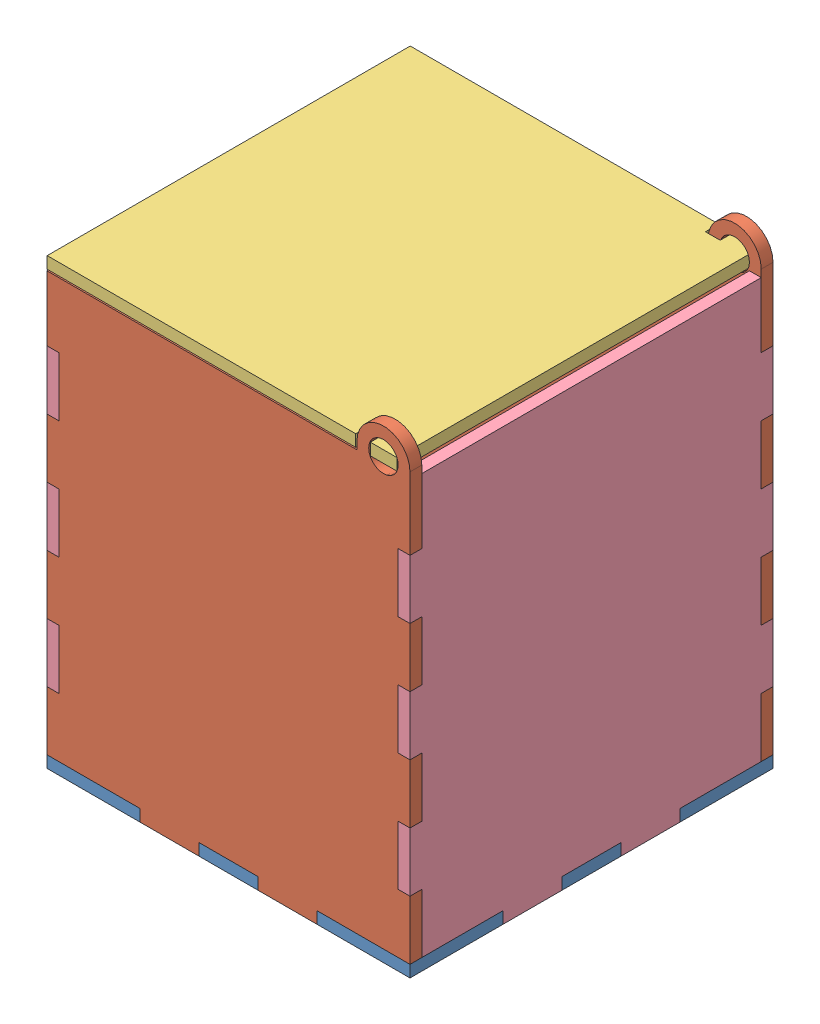
SolidWorks assembly Сборка122, configuration По умолчанию. Lengths in mm.
Overall size (123 157.5 123).
6 component instances, 4 part files, 16 mates.
Components (placement in the parent):
- Дно-1: Дно [По умолчанию] at origin size (123 4 123)
- БокСОтв-1: БокСОтв [По умолчанию] at (0 4 -4) size (123 157.5 4)
- БокСОтв-2: БокСОтв [По умолчанию] at (0 4 -123) size (123 157.5 4)
- Крышка-1: Крышка [По умолчанию] at (0.0826 150.5 -61.5) x (0 0 -1) z (-1 0 0) size (123 4 118.5)
- ПередСтенка-1: ПередСтенка [По умолчанию] at (0 4 -4) x (0 0 -1) z (1 0 0) size (123 146 4)
- ПередСтенка-2: ПередСтенка [По умолчанию] at (119 4 -4) x (0 0 -1) z (1 0 0) size (123 146 4)
Mates (geometry in assembly coordinates):
- Совпадение1: coincident aligned: plane of Дно-1 through (0 4 0) normal (0 0 1); plane of БокСОтв-1 through (114 148.5 0) normal (0 0 1)
- Совпадение2: coincident aligned: plane of Дно-1 through (0 0 0) normal (0 -1 0); plane of БокСОтв-1 through (71.5 0 0) normal (0 -1 0)
- Совпадение3: coincident aligned: plane of Дно-1 through (123 4 0) normal (1 0 0); plane of БокСОтв-1 through (123 4 0) normal (1 0 0)
- Совпадение4: coincident aligned: plane of БокСОтв-1 through (0 4 0) normal (-1 0 0); plane of БокСОтв-2 through (0 4 -119) normal (-1 0 0)
- Совпадение5: coincident aligned: plane of Дно-1 through (51.5 4 -123) normal (0 0 -1); plane of БокСОтв-2 through (114 148.5 -123) normal (0 0 -1)
- Совпадение6: coincident aligned: plane of Дно-1 through (0 0 0) normal (0 -1 0); plane of БокСОтв-2 through (31.5 0 -119) normal (0 -1 0)
- Совпадение7: coincident: cylinder of БокСОтв-1 through (114 148.5 0) axis (0 0 -1) radius 5; line of Крышка-1 through (118.5826 146.5 -123) axis (0 0 1)
- Совпадение8: coincident aligned: plane of БокСОтв-1 through (114 148.5 0) normal (0 0 1); plane of Крышка-1 through (109.5826 146.5 0) normal (0 0 1)
- Совпадение9: coincident: cylinder of БокСОтв-1 through (114 148.5 0) axis (0 0 -1) radius 5; line of Крышка-1 through (118.5826 150.5 -123) axis (0 0 1)
- Совпадение10: coincident anti-aligned: plane of Дно-1 through (4 4 -51.5) normal (-1 0 0); plane of ПередСтенка-1 through (4 4 -4) normal (1 0 0)
- Совпадение11: coincident aligned: plane of Дно-1 through (0 0 0) normal (0 -1 0); plane of ПередСтенка-1 through (4 0 -31.5) normal (0 -1 0)
- Совпадение12: coincident anti-aligned: plane of БокСОтв-1 through (114 148.5 -4) normal (0 0 -1); plane of ПередСтенка-1 through (4 4 -4) normal (0 0 1)
- Совпадение13: coincident anti-aligned: plane of БокСОтв-1 through (114 148.5 -4) normal (0 0 -1); plane of ПередСтенка-2 through (123 4 -4) normal (0 0 1)
- Совпадение14: coincident aligned: plane of Дно-1 through (0 0 0) normal (0 -1 0); plane of ПередСтенка-2 through (123 0 -91.5) normal (0 -1 0)
- Совпадение15: coincident aligned: plane of БокСОтв-2 through (123 4 -119) normal (1 0 0); plane of ПередСтенка-2 through (123 4 -4) normal (1 0 0)
- Граничный угол1: limit planar angle = 1.570796 rad anti-aligned: plane of Крышка-1 through (0.0826 150.5 -61.5) normal (0 1 0); plane of ПередСтенка-2 through (123 4 -4) normal (1 0 0)
